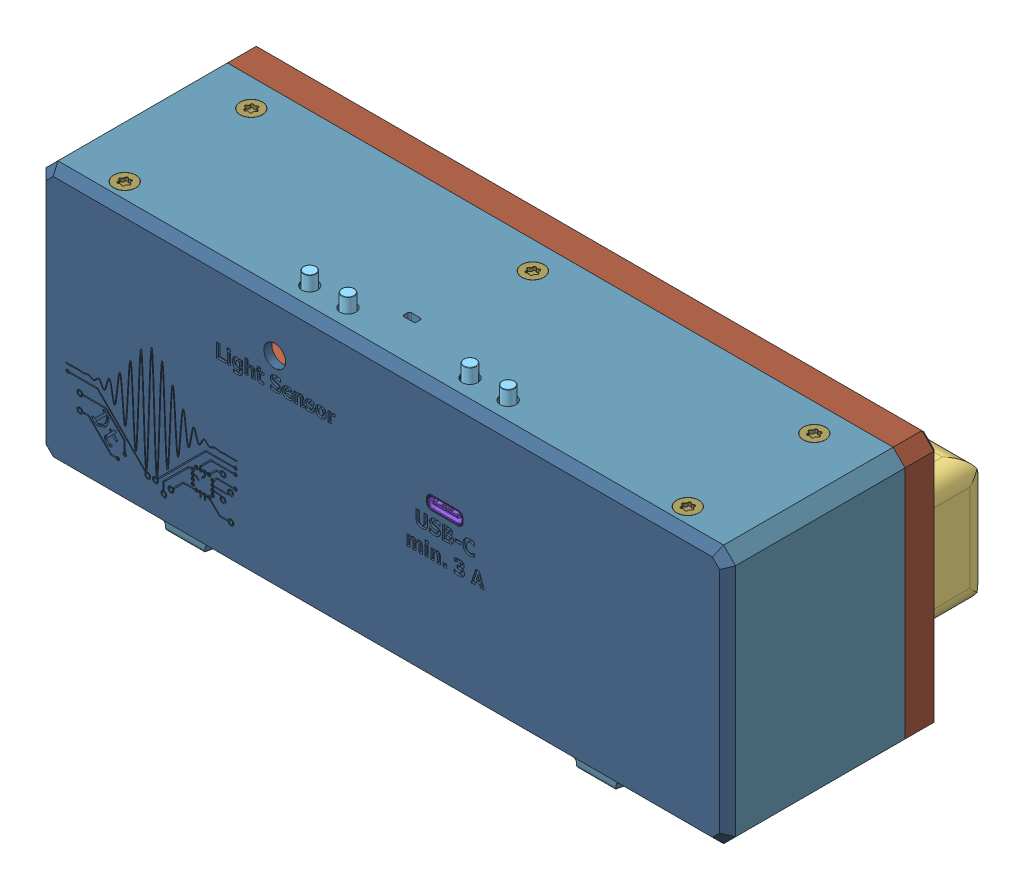
SolidWorks assembly VFDClock_assembly, configuration Default. Lengths in mm.
Overall size (173.3 78.19 72.6).
198 component instances, 48 part files, 101 mates.
Components (placement in the parent):
- Module.step-1: Module.step [Default] at (-86.5239 172.1049 19.515) size (44.41 52.65 19.12)
  - PinSocket_2x03_P2.54mm_Horizontal.step-1: PinSocket_2x03_P2.54mm_Horizontal.step [Default] at (174.37 -130.19 1.595) x (-1 0 0) z (0 0 1) size (12.67 7.62 7.98)
  - D_0603_1608Metric.step-1: D_0603_1608Metric.step [Default] at (176.575 -96 1.595) x (0 -1 0) z (0 0 1) size (1.6 0.87 0.66)
  - TSSOP-16_4.4x5mm_P0.65mm.step-1: TSSOP-16_4.4x5mm_P0.65mm.step [Default] at (164.8375 -99.8 1.595) x (0 -1 0) z (0 0 1) size (6.4 5 1.1)
  - SSOP-18_4.4x6.5mm_P0.65mm.step-1: SSOP-18_4.4x6.5mm_P0.65mm.step [Default] at (164.8375 -91.34 1.595) size (6.4 6.5 1.4)
  - PinSocket_2x03_P2.54mm_Horizontal.step-2: PinSocket_2x03_P2.54mm_Horizontal.step [Default] at (155.23 -116.36 1.595) size (12.67 7.62 7.98)
  - CP_EIA-3216-18_Kemet-A.step-1: CP_EIA-3216-18_Kemet-A.step [Default] at (179.98 -105.55 1.595) x (-1 0 0) z (0 0 1) size (3.2 1.6 1.8)
  - L_1812_4532Metric.step-1: L_1812_4532Metric.step [Default] at (179.98 -101.7575 1.595) x (0 1 0) z (0 0 1) size (4.5 3.2 2.5)
  - PinSocket_2x03_P2.54mm_Horizontal.step-3: PinSocket_2x03_P2.54mm_Horizontal.step [Default] at (155.23 -125.11 1.595) size (12.67 7.62 7.98)
  - D_0603_1608Metric.step-2: D_0603_1608Metric.step [Default] at (157.5 -96 1.595) x (0 -1 0) z (0 0 1) size (1.6 0.87 0.66)
  - PinSocket_2x03_P2.54mm_Horizontal.step-4: PinSocket_2x03_P2.54mm_Horizontal.step [Default] at (174.375 -121.44 1.595) x (-1 0 0) z (0 0 1) size (12.67 7.62 7.98)
  - SOT-223.step-1: SOT-223.step [Default] at (164.8375 -126.74 1.595) x (0 1 0) z (0 0 1) size (7 6.5 1.7)
  - C_0805_2012Metric.step-1: C_0805_2012Metric.step [Default] at (179.98 -98.05 1.595) size (2 1.25 1.25)
  - SOT-223.step-2: SOT-223.step [Default] at (164.8375 -108.8 1.595) x (0 1 0) z (0 0 1) size (7 6.5 1.7)
  - Potentiometer_Bourns_3339P_Vertical.step-1: Potentiometer_Bourns_3339P_Vertical.step [Default] at (162.3275 -117.8 1.595) x (0 -1 0) z (0 0 1) size (7.62 7.62 11.13)
  - CP_EIA-3528-15_AVX-H.step-1: CP_EIA-3528-15_AVX-H.step [Default] at (163.7 -107.7575 -0.085) x (0 -1 0) z (0 0 -1) size (3.5 2.8 1.5)
  - C_0805_2012Metric.step-2: C_0805_2012Metric.step [Default] at (166.5337 -111.3575 -0.085) x (-1 0 0) z (0 0 -1) size (2 1.25 1.25)
  - C_0805_2012Metric.step-3: C_0805_2012Metric.step [Default] at (163.1037 -129.2975 -0.085) x (1 0 0) z (0 0 -1) size (2 1.25 1.25)
  - CP_EIA-3216-18_Kemet-A.step-2: CP_EIA-3216-18_Kemet-A.step [Default] at (166.5375 -125.6975 -0.085) x (0 -1 0) z (0 0 -1) size (3.2 1.6 1.8)
  - C_0805_2012Metric.step-4: C_0805_2012Metric.step [Default] at (163.0662 -111.3575 -0.085) x (1 0 0) z (0 0 -1) size (2 1.25 1.25)
  - CP_EIA-3528-15_AVX-H.step-2: CP_EIA-3528-15_AVX-H.step [Default] at (163.7375 -125.6975 -0.085) x (0 -1 0) z (0 0 -1) size (3.5 2.8 1.5)
  - CP_EIA-3216-18_Kemet-A.step-3: CP_EIA-3216-18_Kemet-A.step [Default] at (166.5 -107.7575 -0.085) x (0 -1 0) z (0 0 -1) size (3.2 1.6 1.8)
  - Module 1.22.step-1: Module 1.22.step [Default] at (182 -101.5275 -0.0739) x (0 1 0) z (-1 0 0) size (21.8 15.2 9.23)
  - C_0805_2012Metric.step-5: C_0805_2012Metric.step [Default] at (166.5712 -129.2975 -0.085) x (-1 0 0) z (0 0 -1) size (2 1.25 1.25)
  - Module_silkscreen.step-1: Module_silkscreen.step [Default] at origin size (44.41 49.93 1.67)
  - Module_PCB.step-1: Module_PCB.step [Default] at origin size (44.4 52.65 1.51)
- Module.step-2: Module.step [Default] at (-210.9239 172.1049 19.515) size (44.41 52.65 19.12)
  - PinSocket_2x03_P2.54mm_Horizontal.step-1: PinSocket_2x03_P2.54mm_Horizontal.step [Default] at (174.37 -130.19 1.595) x (-1 0 0) z (0 0 1) size (12.67 7.62 7.98)
  - D_0603_1608Metric.step-1: D_0603_1608Metric.step [Default] at (176.575 -96 1.595) x (0 -1 0) z (0 0 1) size (1.6 0.87 0.66)
  - TSSOP-16_4.4x5mm_P0.65mm.step-1: TSSOP-16_4.4x5mm_P0.65mm.step [Default] at (164.8375 -99.8 1.595) x (0 -1 0) z (0 0 1) size (6.4 5 1.1)
  - SSOP-18_4.4x6.5mm_P0.65mm.step-1: SSOP-18_4.4x6.5mm_P0.65mm.step [Default] at (164.8375 -91.34 1.595) size (6.4 6.5 1.4)
  - PinSocket_2x03_P2.54mm_Horizontal.step-2: PinSocket_2x03_P2.54mm_Horizontal.step [Default] at (155.23 -116.36 1.595) size (12.67 7.62 7.98)
  - CP_EIA-3216-18_Kemet-A.step-1: CP_EIA-3216-18_Kemet-A.step [Default] at (179.98 -105.55 1.595) x (-1 0 0) z (0 0 1) size (3.2 1.6 1.8)
  - L_1812_4532Metric.step-1: L_1812_4532Metric.step [Default] at (179.98 -101.7575 1.595) x (0 1 0) z (0 0 1) size (4.5 3.2 2.5)
  - PinSocket_2x03_P2.54mm_Horizontal.step-3: PinSocket_2x03_P2.54mm_Horizontal.step [Default] at (155.23 -125.11 1.595) size (12.67 7.62 7.98)
  - D_0603_1608Metric.step-2: D_0603_1608Metric.step [Default] at (157.5 -96 1.595) x (0 -1 0) z (0 0 1) size (1.6 0.87 0.66)
  - PinSocket_2x03_P2.54mm_Horizontal.step-4: PinSocket_2x03_P2.54mm_Horizontal.step [Default] at (174.375 -121.44 1.595) x (-1 0 0) z (0 0 1) size (12.67 7.62 7.98)
  - SOT-223.step-1: SOT-223.step [Default] at (164.8375 -126.74 1.595) x (0 1 0) z (0 0 1) size (7 6.5 1.7)
  - C_0805_2012Metric.step-1: C_0805_2012Metric.step [Default] at (179.98 -98.05 1.595) size (2 1.25 1.25)
  - SOT-223.step-2: SOT-223.step [Default] at (164.8375 -108.8 1.595) x (0 1 0) z (0 0 1) size (7 6.5 1.7)
  - Potentiometer_Bourns_3339P_Vertical.step-1: Potentiometer_Bourns_3339P_Vertical.step [Default] at (162.3275 -117.8 1.595) x (0 -1 0) z (0 0 1) size (7.62 7.62 11.13)
  - CP_EIA-3528-15_AVX-H.step-1: CP_EIA-3528-15_AVX-H.step [Default] at (163.7 -107.7575 -0.085) x (0 -1 0) z (0 0 -1) size (3.5 2.8 1.5)
  - C_0805_2012Metric.step-2: C_0805_2012Metric.step [Default] at (166.5337 -111.3575 -0.085) x (-1 0 0) z (0 0 -1) size (2 1.25 1.25)
  - C_0805_2012Metric.step-3: C_0805_2012Metric.step [Default] at (163.1037 -129.2975 -0.085) x (1 0 0) z (0 0 -1) size (2 1.25 1.25)
  - CP_EIA-3216-18_Kemet-A.step-2: CP_EIA-3216-18_Kemet-A.step [Default] at (166.5375 -125.6975 -0.085) x (0 -1 0) z (0 0 -1) size (3.2 1.6 1.8)
  - C_0805_2012Metric.step-4: C_0805_2012Metric.step [Default] at (163.0662 -111.3575 -0.085) x (1 0 0) z (0 0 -1) size (2 1.25 1.25)
  - CP_EIA-3528-15_AVX-H.step-2: CP_EIA-3528-15_AVX-H.step [Default] at (163.7375 -125.6975 -0.085) x (0 -1 0) z (0 0 -1) size (3.5 2.8 1.5)
  - CP_EIA-3216-18_Kemet-A.step-3: CP_EIA-3216-18_Kemet-A.step [Default] at (166.5 -107.7575 -0.085) x (0 -1 0) z (0 0 -1) size (3.2 1.6 1.8)
  - Module 1.22.step-1: Module 1.22.step [Default] at (182 -101.5275 -0.0739) x (0 1 0) z (-1 0 0) size (21.8 15.2 9.23)
  - C_0805_2012Metric.step-5: C_0805_2012Metric.step [Default] at (166.5712 -129.2975 -0.085) x (-1 0 0) z (0 0 -1) size (2 1.25 1.25)
  - Module_silkscreen.step-1: Module_silkscreen.step [Default] at origin size (44.41 49.93 1.67)
  - Module_PCB.step-1: Module_PCB.step [Default] at origin size (44.4 52.65 1.51)
- Case-1: Case [Default] at (-0.4461 33.1192 -13.485) size (173.3 74.82 42.72)
- VFDClock.step-3: VFDClock.step [Default] at (-132.7539 172.5049 19.515) size (91.66 58.3 22.77)
  - VEML3235SL.step-1: VEML3235SL.step [Default] at (143.765 -88.9975 -0.835) x (1 0 0) z (0 1 0) size (3.18 1.51 1.66)
    - terminal^Vishay_-_VEML3235SL.step.step-1: terminal^Vishay_-_VEML3235SL.step.step [Default] at origin size (3.18 0.48 0.44)
    - base.step.step-1: base.step.step [Default] at origin size (2.95 1.5 1.05)
    - top^Vishay_-_VEML3235SL.step.step-1: top^Vishay_-_VEML3235SL.step.step [Default] at (0 0 1.05) size (2.95 1.5 0.6)
    - logo^Vishay_-_VEML3235SL.step.step-1: logo^Vishay_-_VEML3235SL.step.step [Default] at (0 0 1.65) size (2.81 0.54 0.01)
  - SOT-323_SC-70.step-1: SOT-323_SC-70.step [Default] at (130.3 -90.355 1.595) x (0 -1 0) z (0 0 1) size (2 2 1.05)
  - LED_0603_1608Metric.step-1: LED_0603_1608Metric.step [Default] at (164.03 -88.68 1.595) x (-1 0 0) z (0 0 1) size (1.6 0.8 1.1)
  - PinHeader_2x03_P2.54mm_Horizontal.step-1: PinHeader_2x03_P2.54mm_Horizontal.step [Default] at (182.08 -125.51 1.595) size (12.9 7.62 8.08)
  - D_0603_1608Metric.step-1: D_0603_1608Metric.step [Default] at (144.73 -127.58 1.595) size (1.6 0.87 0.66)
  - TSSOP-16_4.4x5mm_P0.65mm.step-1: TSSOP-16_4.4x5mm_P0.65mm.step [Default] at (140.03 -116.68 1.595) x (0 1 0) z (0 0 1) size (6.4 5 1.1)
  - SSOP-18_4.4x6.5mm_P0.65mm.step-1: SSOP-18_4.4x6.5mm_P0.65mm.step [Default] at (148.79 -116.68 1.595) x (0 -1 0) z (0 0 1) size (6.4 6.5 1.4)
  - R_0805_2012Metric.step-1: R_0805_2012Metric.step [Default] at (160.53 -90.48 1.595) x (-1 0 0) z (0 0 1) size (2 1.2 0.45)
  - PinHeader_2x03_P2.54mm_Horizontal.step-2: PinHeader_2x03_P2.54mm_Horizontal.step [Default] at (115.58 -121.84 1.595) x (-1 0 0) z (0 0 1) size (12.9 7.62 8.08)
  - SSOP-18_4.4x6.5mm_P0.65mm.step-2: SSOP-18_4.4x6.5mm_P0.65mm.step [Default] at (158.43 -116.68 1.595) x (0 -1 0) z (0 0 1) size (6.4 6.5 1.4)
  - SW_Tactile_SPST_Angled_PTS645Vx83-2LFS.step-1: SW_Tactile_SPST_Angled_PTS645Vx83-2LFS.step [Default] at (131.33 -82.0425 1.595) size (7.4 12.4 11)
  - R_0805_2012Metric.step-2: R_0805_2012Metric.step [Default] at (162.53 -96.8 1.595) size (2 1.2 0.45)
  - PTS810SJK250SMTR_LFS-v2.step-1: PTS810SJK250SMTR_LFS-v2.step [Default] at (134.63 -88.48 1.595) x (1 0 0) z (0 -1 0) size (4.6 2.7 3.2)
  - R_0805_2012Metric.step-3: R_0805_2012Metric.step [Default] at (137.43 -97.18 1.595) x (0 -1 0) z (0 0 1) size (2 1.2 0.45)
  - R_0805_2012Metric.step-4: R_0805_2012Metric.step [Default] at (137.43 -100.58 1.595) x (0 1 0) z (0 0 1) size (2 1.2 0.45)
  - SW_Tactile_SPST_Angled_PTS645Vx83-2LFS.step-2: SW_Tactile_SPST_Angled_PTS645Vx83-2LFS.step [Default] at (161.98 -82.0425 1.595) size (7.4 12.4 11)
  - PinSocket_2x04_P2.54mm_Vertical_SMD.step-1: PinSocket_2x04_P2.54mm_Vertical_SMD.step [Default] at (171.5 -91.1 1.595) x (0 1 0) z (0 0 1) size (6.8 10.16 7.45)
  - LED_0603_1608Metric.step-2: LED_0603_1608Metric.step [Default] at (160.53 -88.68 1.595) x (-1 0 0) z (0 0 1) size (1.6 0.8 1.1)
  - SW_Tactile_SPST_Angled_PTS645Vx83-2LFS.step-3: SW_Tactile_SPST_Angled_PTS645Vx83-2LFS.step [Default] at (171.59 -82.0425 1.595) size (7.4 12.4 11)
  - CP_EIA-3216-18_Kemet-A.step-1: CP_EIA-3216-18_Kemet-A.step [Default] at (179.6925 -112.1 1.595) x (0 -1 0) z (0 0 1) size (3.2 1.6 1.8)
  - UJ20-C-V-C-2-SMT-TR-v2.step-1: UJ20-C-V-C-2-SMT-TR-v2.step [Default] at (164.43 -102.6 1.595) x (1 0 0) z (0 -1 0) size (9.5 12.25 4.16)
  - ESP32-S3-WROOM-1.step-1: ESP32-S3-WROOM-1.step [Default] at (148.93 -93.58 1.595) size (18 25.5 3.1)
  - C_0805_2012Metric.step-1: C_0805_2012Metric.step [Default] at (131.13 -95.18 1.595) x (-1 0 0) z (0 0 1) size (2 1.25 1.25)
  - R_0805_2012Metric.step-5: R_0805_2012Metric.step [Default] at (166.23 -96.8 1.595) size (2 1.2 0.45)
  - R_0805_2012Metric.step-6: R_0805_2012Metric.step [Default] at (164.03 -90.48 1.595) x (-1 0 0) z (0 0 1) size (2 1.2 0.45)
  - R_0805_2012Metric.step-7: R_0805_2012Metric.step [Default] at (121.63 -94.28 1.595) x (-1 0 0) z (0 0 1) size (2 1.2 0.45)
  - C_0805_2012Metric.step-2: C_0805_2012Metric.step [Default] at (129.33 -102.58 1.595) x (-1 0 0) z (0 0 1) size (2 1.25 1.25)
  - R_0805_2012Metric.step-8: R_0805_2012Metric.step [Default] at (162.53 -98.8 1.595) size (2 1.2 0.45)
  - R_0805_2012Metric.step-9: R_0805_2012Metric.step [Default] at (166.23 -98.8 1.595) x (-1 0 0) z (0 0 1) size (2 1.2 0.45)
  - L_1812_4532Metric.step-1: L_1812_4532Metric.step [Default] at (175.9 -112.1 1.595) x (-1 0 0) z (0 0 1) size (4.5 3.2 2.5)
  - PinHeader_2x03_P2.54mm_Horizontal.step-3: PinHeader_2x03_P2.54mm_Horizontal.step [Default] at (115.58 -130.59 1.595) x (-1 0 0) z (0 0 1) size (12.9 7.62 8.08)
  - SOIC-8_3.9x4.9mm_P1.27mm.step-1: SOIC-8_3.9x4.9mm_P1.27mm.step [Default] at (131.13 -98.88 1.595) size (6 4.9 1.75)
  - C_0805_2012Metric.step-3: C_0805_2012Metric.step [Default] at (132.93 -102.58 1.595) size (2 1.25 1.25)
  - PTS810SJK250SMTR_LFS-v2.step-2: PTS810SJK250SMTR_LFS-v2.step [Default] at (134.63 -92.28 1.595) x (1 0 0) z (0 -1 0) size (4.6 2.7 3.2)
  - D_0603_1608Metric.step-2: D_0603_1608Metric.step [Default] at (147.83 -127.58 1.595) size (1.6 0.87 0.66)
  - PinHeader_2x03_P2.54mm_Horizontal.step-4: PinHeader_2x03_P2.54mm_Horizontal.step [Default] at (182.08 -116.76 1.595) size (12.9 7.62 8.08)
  - SOT-223.step-1: SOT-223.step [Default] at (183.7675 -100.4 1.595) x (0 -1 0) z (0 0 1) size (7 6.5 1.7)
  - PinSocket_2x02_P2.54mm_Vertical_SMD.step-1: PinSocket_2x02_P2.54mm_Vertical_SMD.step [Default] at (183.83 -83.28 1.595) size (6.8 5.08 7.45)
  - C_0805_2012Metric.step-4: C_0805_2012Metric.step [Default] at (172.1925 -112.1 1.595) x (0 1 0) z (0 0 1) size (2 1.25 1.25)
  - SOT-223.step-2: SOT-223.step [Default] at (174.3 -100.4 1.595) x (0 -1 0) z (0 0 1) size (7 6.5 1.7)
  - R_LDR_5.1x4.3mm_P3.4mm_Vertical.step-1: R_LDR_5.1x4.3mm_P3.4mm_Vertical.step [Default] at (121.63 -88.705 1.595) x (0 -1 0) z (0 0 1) size (5.1 4.3 7)
  - SW_Tactile_SPST_Angled_PTS645Vx83-2LFS.step-4: SW_Tactile_SPST_Angled_PTS645Vx83-2LFS.step [Default] at (121.72 -82.0425 1.595) size (7.4 12.4 11)
  - Potentiometer_Bourns_3339P_Vertical.step-1: Potentiometer_Bourns_3339P_Vertical.step [Default] at (183.805 -88.575 1.595) x (-1 0 0) z (0 0 1) size (7.62 7.62 11.13)
  - R_0805_2012Metric.step-10: R_0805_2012Metric.step [Default] at (142.775 -91.1975 -0.085) x (0 1 0) z (0 0 -1) size (2 1.2 0.45)
  - C_0805_2012Metric.step-5: C_0805_2012Metric.step [Default] at (129.13 -90.48 -0.085) x (0 -1 0) z (0 0 -1) size (2 1.25 1.25)
  - R_0805_2012Metric.step-11: R_0805_2012Metric.step [Default] at (164.22 -84.78 -0.085) x (0 1 0) z (0 0 -1) size (2 1.2 0.45)
  - Fuse_0603_1608Metric.step-1: Fuse_0603_1608Metric.step [Default] at (162.43 -106.28 -0.085) x (1 0 0) z (0 0 -1) size (1.6 0.8 0.45)
  - R_0805_2012Metric.step-12: R_0805_2012Metric.step [Default] at (173.83 -84.78 -0.085) x (0 1 0) z (0 0 -1) size (2 1.2 0.45)
  - SOT-323_SC-70.step-2: SOT-323_SC-70.step [Default] at (164.22 -81.18 -0.085) x (0 -1 0) z (0 0 -1) size (2 2 1.05)
  - CP_EIA-3528-15_AVX-H.step-1: CP_EIA-3528-15_AVX-H.step [Default] at (175.2 -100.15 -0.085) x (0 1 0) z (0 0 -1) size (3.5 2.8 1.5)
  - SOT-323_SC-70.step-3: SOT-323_SC-70.step [Default] at (133.59 -81.18 -0.085) x (0 -1 0) z (0 0 -1) size (2 2 1.05)
  - R_0805_2012Metric.step-13: R_0805_2012Metric.step [Default] at (133.605 -84.78 -0.085) x (0 1 0) z (0 0 -1) size (2 1.2 0.45)
  - C_0805_2012Metric.step-6: C_0805_2012Metric.step [Default] at (172.5 -103.75 -0.085) x (1 0 0) z (0 0 -1) size (2 1.25 1.25)
  - R_0805_2012Metric.step-14: R_0805_2012Metric.step [Default] at (126.43 -88.48 -0.085) x (-1 0 0) z (0 0 -1) size (2 1.2 0.45)
  - SOT-323_SC-70.step-4: SOT-323_SC-70.step [Default] at (173.83 -81.18 -0.085) x (0 -1 0) z (0 0 -1) size (2 2 1.05)
  - JST_XH_B4B-XH-A_1x04_P2.50mm_Vertical.step-1: JST_XH_B4B-XH-A_1x04_P2.50mm_Vertical.step [Default] at (168.78 -121.58 -0.085) x (0 -1 0) z (0 0 -1) size (12.4 5.75 10.4)
  - SC-74-6_1.55x2.9mm_P0.95mm.step-1: SC-74-6_1.55x2.9mm_P0.95mm.step [Default] at (162.43 -110.2 -0.085) x (0 1 0) z (0 0 -1) size (2.7 2.9 1.18)
  - C_0805_2012Metric.step-7: C_0805_2012Metric.step [Default] at (137.63 -92.28 -0.085) x (0 -1 0) z (0 0 -1) size (2 1.25 1.25)
  - R_0805_2012Metric.step-15: R_0805_2012Metric.step [Default] at (133.5483 -88.63 -0.085) x (0 1 0) z (0 0 -1) size (2 1.2 0.45)
  - CP_EIA-3216-18_Kemet-A.step-2: CP_EIA-3216-18_Kemet-A.step [Default] at (146.96 -89.3475 -0.085) x (0 -1 0) z (0 0 -1) size (3.2 1.6 1.8)
  - C_0805_2012Metric.step-8: C_0805_2012Metric.step [Default] at (185.6 -103.7625 -0.085) x (-1 0 0) z (0 0 -1) size (2 1.25 1.25)
  - BatteryHolder_Keystone_3034_1x20mm.step-1: BatteryHolder_Keystone_3034_1x20mm.step [Default] at (128.93 -106.7 -0.085) x (0 1 0) z (0 0 -1) size (23.24 16.41 4)
  - CP_EIA-3216-18_Kemet-A.step-3: CP_EIA-3216-18_Kemet-A.step [Default] at (182 -100.1625 -0.085) x (0 -1 0) z (0 0 -1) size (3.2 1.6 1.8)
  - C_0805_2012Metric.step-9: C_0805_2012Metric.step [Default] at (176.2 -103.75 -0.085) x (-1 0 0) z (0 0 -1) size (2 1.25 1.25)
  - R_0805_2012Metric.step-16: R_0805_2012Metric.step [Default] at (123.995 -84.78 -0.085) x (0 1 0) z (0 0 -1) size (2 1.2 0.45)
  - C_0805_2012Metric.step-10: C_0805_2012Metric.step [Default] at (149.06 -89.3475 -0.085) x (0 -1 0) z (0 0 -1) size (2 1.25 1.25)
  - SOT-323_SC-70.step-5: SOT-323_SC-70.step [Default] at (123.98 -81.18 -0.085) x (0 -1 0) z (0 0 -1) size (2 2 1.05)
  - C_0805_2012Metric.step-11: C_0805_2012Metric.step [Default] at (137.7 -88.6255 -0.085) x (0 1 0) z (0 0 -1) size (2 1.25 1.25)
  - CP_EIA-3528-15_AVX-H.step-2: CP_EIA-3528-15_AVX-H.step [Default] at (184.9 -100.1625 -0.085) x (0 1 0) z (0 0 -1) size (3.5 2.8 1.5)
  - C_0805_2012Metric.step-12: C_0805_2012Metric.step [Default] at (135.63 -92.28 -0.085) x (0 -1 0) z (0 0 -1) size (2 1.25 1.25)
  - CP_EIA-3216-18_Kemet-A.step-4: CP_EIA-3216-18_Kemet-A.step [Default] at (135.6183 -88 -0.085) x (0 1 0) z (0 0 -1) size (3.2 1.6 1.8)
  - SHT45-AD1B-R2.step-1: SHT45-AD1B-R2.step [Default] at (126.43 -90.48 -0.085) x (1 0 0) z (0 1 0) size (1.5 0.69 1.5)
  - CP_EIA-3216-18_Kemet-A.step-5: CP_EIA-3216-18_Kemet-A.step [Default] at (172.3 -100.15 -0.085) x (0 -1 0) z (0 0 -1) size (3.2 1.6 1.8)
  - R_0805_2012Metric.step-17: R_0805_2012Metric.step [Default] at (144.83 -91.1975 -0.085) x (0 1 0) z (0 0 -1) size (2 1.2 0.45)
  - R_0805_2012Metric.step-18: R_0805_2012Metric.step [Default] at (133.63 -92.28 -0.085) x (0 1 0) z (0 0 -1) size (2 1.2 0.45)
  - JST_XH_B4B-XH-A_1x04_P2.50mm_Vertical.step-2: JST_XH_B4B-XH-A_1x04_P2.50mm_Vertical.step [Default] at (128.84 -121.58 -0.085) x (0 -1 0) z (0 0 -1) size (12.4 5.75 10.4)
  - VFDClock 1.77.step-1: VFDClock 1.77.step [Default] at (175.67 -110.08 -0.0739) x (-1 0 0) z (0 -1 0) size (21.8 15.2 9.23)
  - C_0805_2012Metric.step-13: C_0805_2012Metric.step [Default] at (181.9 -103.7625 -0.085) x (1 0 0) z (0 0 -1) size (2 1.25 1.25)
  - R_0805_2012Metric.step-19: R_0805_2012Metric.step [Default] at (126.43 -92.48 -0.085) x (-1 0 0) z (0 0 -1) size (2 1.2 0.45)
  - VFDClock_silkscreen.step-1: VFDClock_silkscreen.step [Default] at origin size (80.01 52.34 1.76)
  - VFDClock_PCB.step-1: VFDClock_PCB.step [Default] at origin size (80 52.65 1.51)
- IV-22-1: IV-22 [Default] at (-53.4239 62.8549 -13.485) x (-1 0 0) z (0 0 -1) size (22 32 36)
- PL31A-P-1: PL31A-P [Default] at (-73.9735 62.8549 -6.685) x (-1 0 0) z (0 0 -1) size (22 40.86 14.1)
- PL31A-P-19: PL31A-P [Default] at (-50.5735 62.8549 -6.685) x (-1 0 0) z (0 0 -1) size (22 40.86 14.1)
- PL31A-P-20: PL31A-P [Default] at (-16.1735 62.8549 -6.685) x (-1 0 0) z (0 0 -1) size (22 40.86 14.1)
- PL31A-P-21: PL31A-P [Default] at (7.2265 62.8549 -6.685) x (-1 0 0) z (0 0 -1) size (22 40.86 14.1)
- PL31A-P-22: PL31A-P [Default] at (41.6265 62.8549 -6.685) x (-1 0 0) z (0 0 -1) size (22 40.86 14.1)
- IV-22-23: IV-22 [Default] at (85.5761 62.8549 -13.485) x (-1 0 0) z (0 0 -1) size (22 32 36)
- PL31A-P-23: PL31A-P [Default] at (65.0265 62.8549 -6.685) x (-1 0 0) z (0 0 -1) size (22 40.86 14.1)
- Separator.step-1: Separator.step [Default] at (-67.0239 202.8549 -11.685) x (0 -1 0) z (0 0 -1) size (32 10 9.38)
  - LED_Inolux_IN-PI554FCH_PLCC4_5.0x5.0mm_P3.2mm.step-1: LED_Inolux_IN-PI554FCH_PLCC4_5.0x5.0mm_P3.2mm.step [Default] at (144.6 -112 1.595) x (0 -1 0) z (0 0 1) size (5.4 5 1.7)
  - LED_Inolux_IN-PI554FCH_PLCC4_5.0x5.0mm_P3.2mm.step-2: LED_Inolux_IN-PI554FCH_PLCC4_5.0x5.0mm_P3.2mm.step [Default] at (135 -112 1.595) x (0 1 0) z (0 0 1) size (5.4 5 1.7)
  - PinHeader_2x02_P2.00mm_Vertical.step-1: PinHeader_2x02_P2.00mm_Vertical.step [Default] at (138.8 -111.1 -0.085) x (0 -1 0) z (0 0 -1) size (4 4 8.8)
  - R_0805_2012Metric.step-1: R_0805_2012Metric.step [Default] at (140 -108.6 -0.085) x (-1 0 0) z (0 0 -1) size (2 1.2 0.45)
  - SOT-23.step-1: SOT-23.step [Default] at (135.3 -112 -0.085) x (-1 0 0) z (0 0 -1) size (2.5 3 1.2)
  - C_0805_2012Metric.step-1: C_0805_2012Metric.step [Default] at (143.3 -112 -0.085) x (0 -1 0) z (0 0 -1) size (2 1.25 1.25)
  - R_0805_2012Metric.step-2: R_0805_2012Metric.step [Default] at (140 -115.6 -0.085) x (-1 0 0) z (0 0 -1) size (2 1.2 0.45)
  - C_0805_2012Metric.step-2: C_0805_2012Metric.step [Default] at (132.3 -112 -0.085) x (0 -1 0) z (0 0 -1) size (2 1.25 1.25)
  - Separator_silkscreen.step-1: Separator_silkscreen.step [Default] at origin size (25.16 9.28 1.67)
  - Separator_PCB.step-1: Separator_PCB.step [Default] at origin size (32 10 1.51)
- Separator.step-2: Separator.step [Default] at (-124.8239 202.8549 -11.685) x (0 -1 0) z (0 0 -1) size (32 10 9.38)
  - LED_Inolux_IN-PI554FCH_PLCC4_5.0x5.0mm_P3.2mm.step-1: LED_Inolux_IN-PI554FCH_PLCC4_5.0x5.0mm_P3.2mm.step [Default] at (144.6 -112 1.595) x (0 -1 0) z (0 0 1) size (5.4 5 1.7)
  - LED_Inolux_IN-PI554FCH_PLCC4_5.0x5.0mm_P3.2mm.step-2: LED_Inolux_IN-PI554FCH_PLCC4_5.0x5.0mm_P3.2mm.step [Default] at (135 -112 1.595) x (0 1 0) z (0 0 1) size (5.4 5 1.7)
  - PinHeader_2x02_P2.00mm_Vertical.step-1: PinHeader_2x02_P2.00mm_Vertical.step [Default] at (138.8 -111.1 -0.085) x (0 -1 0) z (0 0 -1) size (4 4 8.8)
  - R_0805_2012Metric.step-1: R_0805_2012Metric.step [Default] at (140 -108.6 -0.085) x (-1 0 0) z (0 0 -1) size (2 1.2 0.45)
  - SOT-23.step-1: SOT-23.step [Default] at (135.3 -112 -0.085) x (-1 0 0) z (0 0 -1) size (2.5 3 1.2)
  - C_0805_2012Metric.step-1: C_0805_2012Metric.step [Default] at (143.3 -112 -0.085) x (0 -1 0) z (0 0 -1) size (2 1.25 1.25)
  - R_0805_2012Metric.step-2: R_0805_2012Metric.step [Default] at (140 -115.6 -0.085) x (-1 0 0) z (0 0 -1) size (2 1.2 0.45)
  - C_0805_2012Metric.step-2: C_0805_2012Metric.step [Default] at (132.3 -112 -0.085) x (0 -1 0) z (0 0 -1) size (2 1.25 1.25)
  - Separator_silkscreen.step-1: Separator_silkscreen.step [Default] at origin size (25.16 9.28 1.67)
  - Separator_PCB.step-1: Separator_PCB.step [Default] at origin size (32 10 1.51)
- CaseCover-1: CaseCover [Default] at (19.2559 33.9844 29.115) size (173.3 65 9.8)
- FacePlate-1: FacePlate [Default] at (-21.2345 44.7045 -13.485) x (-1 0 0) z (0 0 -1) size (173.3 65 18.8)
- IV-22-24: IV-22 [Default] at (27.7761 62.8549 -13.485) x (-1 0 0) z (0 0 -1) size (22 32 36)
- IV-22-25: IV-22 [Default] at (-30.0239 62.8549 -13.485) x (-1 0 0) z (0 0 -1) size (22 32 36)
- IV-22-26: IV-22 [Default] at (4.3761 62.8549 -13.485) x (-1 0 0) z (0 0 -1) size (22 32 36)
- IV-22-27: IV-22 [Default] at (62.1761 62.8549 -13.485) x (-1 0 0) z (0 0 -1) size (22 32 36)
- M3x10_Torx-1: M3x10_Torx [Default] at (16.0761 89.4921 -6.585) x (0 -1 0) z (0 0 1) size (10 5.5 5.5)
- M3x10_Torx-2: M3x10_Torx [Default] at (16.0761 36.2176 25.215) x (0 1 0) z (0 0 1) size (10 5.5 5.5)
- M3x10_Torx-4: M3x10_Torx [Default] at (-54.6739 36.2176 -6.585) x (0 1 0) z (0 0 1) size (10 5.5 5.5)
- M3x10_Torx-5: M3x10_Torx [Default] at (86.8261 89.4921 25.215) x (0 -1 0) z (0 0 1) size (10 5.5 5.5)
- M3x10_Torx-6: M3x10_Torx [Default] at (-54.6739 89.4921 -6.585) x (0 -1 0) z (0.1614 0 0.986889) size (10 5.5 5.5)
- M3x10_Torx-7: M3x10_Torx [Default] at (86.8261 36.2176 25.215) x (0 1 0) z (0 0 1) size (10 5.5 5.5)
- M3x10_Torx-8: M3x10_Torx [Default] at (-54.6739 36.2176 25.215) x (0 1 0) z (0 0 1) size (10 5.5 5.5)
- M3x10_Torx-9: M3x10_Torx [Default] at (16.0761 36.2176 -6.585) x (0 1 0) z (0 0 1) size (10 5.5 5.5)
- M3x10_Torx-10: M3x10_Torx [Default] at (86.8261 36.2176 -6.585) x (0 1 0) z (0 0 1) size (10 5.5 5.5)
- M3x10_Torx-11: M3x10_Torx [Default] at (-54.6739 89.4921 25.215) x (0 -1 0) z (0 0 1) size (10 5.5 5.5)
- M3x10_Torx-12: M3x10_Torx [Default] at (86.8261 89.4921 -6.585) x (0 -1 0) z (0 0 1) size (10 5.5 5.5)
- M3x10_Torx-13: M3x10_Torx [Default] at (91.9261 46.3549 -7.6223) x (0 0 1) z (0 1 0) size (10 5.5 5.5)
- M3x10_Torx-14: M3x10_Torx [Default] at (79.2261 79.3549 -7.6223) x (0 0 1) z (0 1 0) size (10 5.5 5.5)
- M3x10_Torx-15: M3x10_Torx [Default] at (55.8261 79.3549 -7.6223) x (0 0 1) z (0 1 0) size (10 5.5 5.5)
- M3x10_Torx-16: M3x10_Torx [Default] at (21.4261 79.3549 -7.6223) x (0 0 1) z (0 1 0) size (10 5.5 5.5)
- M3x10_Torx-17: M3x10_Torx [Default] at (-1.9739 79.3549 -7.6223) x (0 0 1) z (0 1 0) size (10 5.5 5.5)
- M3x10_Torx-18: M3x10_Torx [Default] at (-36.3739 79.3549 -7.6223) x (0 0 1) z (0 1 0) size (10 5.5 5.5)
- M3x10_Torx-19: M3x10_Torx [Default] at (68.5261 46.3549 -7.6223) x (0 0 1) z (0 1 0) size (10 5.5 5.5)
- M3x10_Torx-20: M3x10_Torx [Default] at (34.1261 46.3549 -7.6223) x (0 0 1) z (0 1 0) size (10 5.5 5.5)
- M3x10_Torx-21: M3x10_Torx [Default] at (10.7261 46.3549 -7.6223) x (0 0 1) z (0 1 0) size (10 5.5 5.5)
- M3x10_Torx-22: M3x10_Torx [Default] at (-23.6739 46.3549 -7.6223) x (0 0 1) z (0 1 0) size (10 5.5 5.5)
- M3x10_Torx-23: M3x10_Torx [Default] at (-47.0739 46.3549 -7.6223) x (0 0 1) z (0 1 0) size (10 5.5 5.5)
- M3x10_Torx-24: M3x10_Torx [Default] at (-59.7739 79.3549 -7.6223) x (0 0 1) z (0 1 0) size (10 5.5 5.5)
Mates (geometry in assembly coordinates):
- Concentric11: concentric anti-aligned: cylinder of Module.step-2/Module_PCB.step-1 through (-64.5739 89.3549 19.469) axis (0 0 -1) radius 1.6; cylinder of Case-1 through (-64.5739 89.3549 10.515) axis (0 0 1) radius 2
- Coincident17: coincident anti-aligned: plane of Module.step-2/Module_PCB.step-1 through (-210.9239 172.1049 19.515) normal (0 0 -1); plane of Case-1 through (-64.5739 89.3549 19.515) normal (0 0 1)
- Parallel8: parallel anti-aligned: plane of Module.step-2/Module_PCB.step-1 through (-23.9239 40.4249 19.515) normal (0 -1 0); plane of Case-1 through (-70.5739 32.3549 46.515) normal (0 1 0)
- Coincident18: coincident anti-aligned: plane of Module.step-2/Module_PCB.step-1 through (-23.9239 93.0749 19.515) normal (1 0 0); plane of VFDClock.step-3/VFDClock_PCB.step-1 through (-23.9239 40.4249 19.515) normal (-1 0 0)
- Coincident25: coincident aligned: plane of Module.step-2/Module_PCB.step-1 through (-210.9239 172.1049 21.025) normal (0 0 1); plane of VFDClock.step-3/VFDClock_PCB.step-1 through (-132.7539 172.5049 21.025) normal (0 0 1)
- Coincident26: coincident aligned: plane of Module.step-2/Module_PCB.step-1 through (-68.3239 93.0749 19.515) normal (0 1 0); plane of VFDClock.step-3/VFDClock_PCB.step-1 through (-23.9239 93.0749 19.515) normal (0 1 0)
- Coincident21: coincident anti-aligned: plane of Module.step-1/Module_PCB.step-1 through (56.0761 40.4249 19.515) normal (-1 0 0); plane of VFDClock.step-3/VFDClock_PCB.step-1 through (56.0761 93.0749 19.515) normal (1 0 0)
- Coincident27: coincident aligned: plane of Module.step-1/Module_PCB.step-1 through (-86.5239 172.1049 21.025) normal (0 0 1); plane of VFDClock.step-3/VFDClock_PCB.step-1 through (-132.7539 172.5049 21.025) normal (0 0 1)
- Coincident28: coincident aligned: plane of Module.step-1/Module_PCB.step-1 through (56.0761 93.0749 19.515) normal (0 1 0); plane of VFDClock.step-3/VFDClock_PCB.step-1 through (-23.9239 93.0749 19.515) normal (0 1 0)
- Concentric12: concentric aligned: circle of IV-22-1; cylinder of PL31A-P-1 through (-53.4239 62.8549 4.1932) axis (0 0 -1) radius 2.75
- Parallel13: parallel aligned: plane of IV-22-1 through (-64.4239 73.8549 -41.485) normal (-1 0 0); plane of PL31A-P-1 through (-64.4239 62.8549 -10.485) normal (-1 0 0)
- Coincident23: coincident anti-aligned: plane of IV-22-1 through (-59.4239 51.8549 -13.485) normal (0 0 1); plane of PL31A-P-1 through (-53.4239 62.8549 -13.485) normal (0 0 -1)
- Concentric37: concentric aligned: circle of IV-22-23; cylinder of PL31A-P-23 through (85.5761 62.8549 4.1932) axis (0 0 -1) radius 2.75
- Parallel42: parallel aligned: plane of IV-22-23 through (74.5761 73.8549 -41.485) normal (-1 0 0); plane of PL31A-P-23 through (74.5761 62.8549 -10.485) normal (-1 0 0)
- Coincident64: coincident anti-aligned: plane of IV-22-23 through (79.5761 51.8549 -13.485) normal (0 0 1); plane of PL31A-P-23 through (85.5761 62.8549 -13.485) normal (0 0 -1)
- Concentric40: concentric aligned: cylinder of Case-1 through (-59.7739 79.3549 25.6857) axis (0 0 -1) radius 1.6; cylinder of PL31A-P-1 through (-59.7739 79.3549 -2.0181) axis (0 0 -1) radius 1.65
- Coincident84: coincident aligned: plane of Case-1 through (-0.4461 33.1192 -13.485) normal (0 0 -1); plane of PL31A-P-1 through (-53.4239 62.8549 -13.485) normal (0 0 -1)
- Concentric41: concentric aligned: cylinder of Case-1 through (-47.0739 46.3549 25.6857) axis (0 0 -1) radius 1.6; cylinder of PL31A-P-1 through (-47.0739 46.3549 -2.0181) axis (0 0 -1) radius 1.65
- Coincident85: coincident aligned: plane of Case-1 through (-0.4461 33.1192 -13.485) normal (0 0 -1); plane of PL31A-P-19 through (-30.0239 62.8549 -13.485) normal (0 0 -1)
- Concentric42: concentric aligned: cylinder of Case-1 through (-36.3739 79.3549 25.6857) axis (0 0 -1) radius 1.6; cylinder of PL31A-P-19 through (-36.3739 79.3549 -2.0181) axis (0 0 -1) radius 1.65
- Concentric43: concentric aligned: cylinder of Case-1 through (-23.6739 46.3549 25.6857) axis (0 0 -1) radius 1.6; cylinder of PL31A-P-19 through (-23.6739 46.3549 -2.0181) axis (0 0 -1) radius 1.65
- Coincident86: coincident aligned: plane of Case-1 through (-0.4461 33.1192 -13.485) normal (0 0 -1); plane of PL31A-P-20 through (4.3761 62.8549 -13.485) normal (0 0 -1)
- Concentric44: concentric aligned: cylinder of Case-1 through (-1.9739 79.3549 25.6857) axis (0 0 -1) radius 1.6; cylinder of PL31A-P-20 through (-1.9739 79.3549 -2.0181) axis (0 0 -1) radius 1.65
- Concentric45: concentric aligned: cylinder of Case-1 through (10.7261 46.3549 25.6857) axis (0 0 -1) radius 1.6; cylinder of PL31A-P-20 through (10.7261 46.3549 -2.0181) axis (0 0 -1) radius 1.65
- Coincident87: coincident aligned: plane of Case-1 through (-0.4461 33.1192 -13.485) normal (0 0 -1); plane of PL31A-P-21 through (27.7761 62.8549 -13.485) normal (0 0 -1)
- Concentric46: concentric aligned: cylinder of Case-1 through (21.4261 79.3549 25.6857) axis (0 0 -1) radius 1.6; cylinder of PL31A-P-21 through (21.4261 79.3549 -2.0181) axis (0 0 -1) radius 1.65
- Concentric47: concentric aligned: cylinder of Case-1 through (34.1261 46.3549 25.6857) axis (0 0 -1) radius 1.6; cylinder of PL31A-P-21 through (34.1261 46.3549 -2.0181) axis (0 0 -1) radius 1.65
- Concentric48: concentric aligned: cylinder of Case-1 through (55.8261 79.3549 25.6857) axis (0 0 -1) radius 1.6; cylinder of PL31A-P-22 through (55.8261 79.3549 -2.0181) axis (0 0 -1) radius 1.65
- Coincident88: coincident aligned: plane of Case-1 through (-0.4461 33.1192 -13.485) normal (0 0 -1); plane of PL31A-P-22 through (62.1761 62.8549 -13.485) normal (0 0 -1)
- Concentric49: concentric aligned: cylinder of Case-1 through (68.5261 46.3549 25.6857) axis (0 0 -1) radius 1.6; cylinder of PL31A-P-22 through (68.5261 46.3549 -2.0181) axis (0 0 -1) radius 1.65
- Coincident89: coincident aligned: plane of Case-1 through (-0.4461 33.1192 -13.485) normal (0 0 -1); plane of PL31A-P-23 through (85.5761 62.8549 -13.485) normal (0 0 -1)
- Concentric50: concentric aligned: cylinder of Case-1 through (79.2261 79.3549 25.6857) axis (0 0 -1) radius 1.6; cylinder of PL31A-P-23 through (79.2261 79.3549 -2.0181) axis (0 0 -1) radius 1.65
- Concentric51: concentric aligned: cylinder of Case-1 through (91.9261 46.3549 25.6857) axis (0 0 -1) radius 1.6; cylinder of PL31A-P-23 through (91.9261 46.3549 -2.0181) axis (0 0 -1) radius 1.65
- Coincident90: coincident anti-aligned: plane of Case-1 through (-0.4461 33.1192 -11.685) normal (0 0 -1); plane of Separator.step-1/Separator_PCB.step-1 through (-67.0239 202.8549 -11.685) normal (0 0 1)
- Coincident91: coincident anti-aligned: plane of Case-1 through (-0.4461 33.1192 -11.685) normal (0 0 -1); plane of Separator.step-2/Separator_PCB.step-1 through (-124.8239 202.8549 -11.685) normal (0 0 1)
- Concentric54: concentric anti-aligned: cylinder of Case-1 through (44.9761 74.8549 9.6396) axis (0 0 -1) radius 1.6; cylinder of Separator.step-1/Separator_PCB.step-1 through (44.9761 74.8549 -11.639) axis (0 0 1) radius 1.6
- Concentric55: concentric anti-aligned: cylinder of Case-1 through (-12.8239 74.8549 9.6396) axis (0 0 -1) radius 1.6; cylinder of Separator.step-2/Separator_PCB.step-1 through (-12.8239 74.8549 -11.639) axis (0 0 1) radius 1.6
- Coincident92: coincident anti-aligned: plane of Case-1 through (-0.4461 33.1192 29.115) normal (0 0 1); plane of CaseCover-1 through (19.2559 33.9844 29.115) normal (0 0 -1)
- Coincident97: coincident anti-aligned: plane of Case-1 through (-0.4461 33.1192 -13.485) normal (0 0 -1); plane of FacePlate-1 through (-21.2345 44.7045 -13.485) normal (0 0 1)
- Coincident98: coincident anti-aligned: line of Case-1 through (99.7261 95.3549 -13.485) axis (-1 0 0); line of FacePlate-1 through (-67.5739 95.3549 -13.485) axis (1 0 0)
- Coincident99: coincident anti-aligned: line of Case-1 through (-70.5739 92.3549 -13.485) axis (0 -1 0); line of FacePlate-1 through (-70.5739 33.3549 -13.485) axis (0 1 0)
- Coincident100: coincident aligned: line of Case-1 through (99.7261 95.3549 29.115) axis (-1 0 0); line of CaseCover-1 through (99.7261 95.3549 29.115) axis (-1 0 0)
- Coincident101: coincident aligned: line of Case-1 through (102.7261 33.3549 29.115) axis (0 1 0); line of CaseCover-1 through (102.7261 33.3549 29.115) axis (0 1 0)
- Concentric56: concentric aligned: cylinder of PL31A-P-22 through (62.1761 62.8549 4.1932) axis (0 0 -1) radius 2.75; cylinder of IV-22-27 through (62.1761 62.8549 -5.485) axis (0 0 -1) radius 2.5
- Concentric57: concentric aligned: cylinder of PL31A-P-21 through (27.7761 62.8549 4.1932) axis (0 0 -1) radius 2.75; cylinder of IV-22-24 through (27.7761 62.8549 -5.485) axis (0 0 -1) radius 2.5
- Concentric58: concentric aligned: cylinder of PL31A-P-20 through (4.3761 62.8549 4.1932) axis (0 0 -1) radius 2.75; cylinder of IV-22-26 through (4.3761 62.8549 -5.485) axis (0 0 -1) radius 2.5
- Concentric59: concentric aligned: cylinder of PL31A-P-19 through (-30.0239 62.8549 4.1932) axis (0 0 -1) radius 2.75; cylinder of IV-22-25 through (-30.0239 62.8549 -5.485) axis (0 0 -1) radius 2.5
- Parallel46: parallel: line of PL31A-P-22 through (73.1761 71.5151 -13.485) axis (0 -1 0); plane of IV-22-27 through (73.1761 73.8549 -41.485) normal (1 0 0)
- Parallel45: parallel: line of PL31A-P-21 through (38.7761 71.5151 -13.485) axis (0 -1 0); plane of IV-22-24 through (38.7761 73.8549 -41.485) normal (1 0 0)
- Parallel43: parallel: line of PL31A-P-20 through (15.3761 71.5151 -13.485) axis (0 -1 0); plane of IV-22-26 through (15.3761 73.8549 -41.485) normal (1 0 0)
- Parallel44: parallel: line of PL31A-P-19 through (-19.0239 71.5151 -13.485) axis (0 -1 0); plane of IV-22-25 through (-19.0239 73.8549 -41.485) normal (1 0 0)
- Coincident106: coincident anti-aligned: plane of PL31A-P-22 through (62.1761 62.8549 -13.485) normal (0 0 -1); plane of IV-22-27 through (56.1761 51.8549 -13.485) normal (0 0 1)
- Coincident107: coincident anti-aligned: plane of PL31A-P-21 through (27.7761 62.8549 -13.485) normal (0 0 -1); plane of IV-22-24 through (21.7761 51.8549 -13.485) normal (0 0 1)
- Coincident108: coincident anti-aligned: plane of PL31A-P-20 through (4.3761 62.8549 -13.485) normal (0 0 -1); plane of IV-22-26 through (-1.6239 51.8549 -13.485) normal (0 0 1)
- Coincident109: coincident anti-aligned: plane of PL31A-P-19 through (-30.0239 62.8549 -13.485) normal (0 0 -1); plane of IV-22-25 through (-36.0239 51.8549 -13.485) normal (0 0 1)
- Concentric60: concentric anti-aligned: cylinder of Case-1 through (-54.6739 88.8294 -6.585) axis (0 1 0) radius 1.6; cylinder of M3x10_Torx-6 through (-54.6739 41.3074 -6.585) axis (0 -1 0) radius 1.5
- Coincident110: coincident aligned: plane of Case-1 through (-70.5739 95.3549 46.515) normal (0 1 0); plane of M3x10_Torx-6 through (-51.96 95.3549 -7.0289) normal (0 1 0)
- Concentric61: concentric anti-aligned: cylinder of Case-1 through (16.0761 88.8294 -6.585) axis (0 1 0) radius 1.6; cylinder of M3x10_Torx-1 through (16.0761 41.3074 -6.585) axis (0 -1 0) radius 1.5
- Coincident111: coincident aligned: plane of Case-1 through (-70.5739 95.3549 46.515) normal (0 1 0); plane of M3x10_Torx-1 through (18.8261 95.3549 -6.585) normal (0 1 0)
- Concentric62: concentric anti-aligned: cylinder of Case-1 through (86.8261 88.8294 -6.585) axis (0 1 0) radius 1.6; cylinder of M3x10_Torx-12 through (86.8261 41.3074 -6.585) axis (0 -1 0) radius 1.5
- Coincident112: coincident aligned: plane of Case-1 through (-70.5739 95.3549 46.515) normal (0 1 0); plane of M3x10_Torx-12 through (89.5761 95.3549 -6.585) normal (0 1 0)
- Concentric63: concentric anti-aligned: cylinder of Case-1 through (-54.6739 88.8294 25.215) axis (0 1 0) radius 1.6; cylinder of M3x10_Torx-11 through (-54.6739 41.3074 25.215) axis (0 -1 0) radius 1.5
- Coincident113: coincident aligned: plane of Case-1 through (-70.5739 95.3549 46.515) normal (0 1 0); plane of M3x10_Torx-11 through (-51.9239 95.3549 25.215) normal (0 1 0)
- Concentric64: concentric anti-aligned: cylinder of Case-1 through (86.8261 88.8294 25.215) axis (0 1 0) radius 1.6; cylinder of M3x10_Torx-5 through (86.8261 41.3074 25.215) axis (0 -1 0) radius 1.5
- Coincident114: coincident aligned: plane of Case-1 through (-70.5739 95.3549 46.515) normal (0 1 0); plane of M3x10_Torx-5 through (89.5761 95.3549 25.215) normal (0 1 0)
- Concentric65: concentric anti-aligned: cylinder of Case-1 through (-54.6739 36.8804 -6.585) axis (0 -1 0) radius 1.6; cylinder of M3x10_Torx-4 through (-54.6739 84.4024 -6.585) axis (0 1 0) radius 1.5
- Coincident115: coincident aligned: plane of Case-1 through (-70.5739 30.3549 46.515) normal (0 -1 0); plane of M3x10_Torx-4 through (-57.4239 30.3549 -6.585) normal (0 -1 0)
- Concentric66: concentric anti-aligned: cylinder of Case-1 through (16.0761 36.8804 -6.585) axis (0 -1 0) radius 1.6; cylinder of M3x10_Torx-9 through (16.0761 84.4024 -6.585) axis (0 1 0) radius 1.5
- Coincident116: coincident aligned: plane of Case-1 through (-70.5739 30.3549 46.515) normal (0 -1 0); plane of M3x10_Torx-9 through (13.3261 30.3549 -6.585) normal (0 -1 0)
- Concentric67: concentric anti-aligned: cylinder of Case-1 through (86.8261 36.8804 -6.585) axis (0 -1 0) radius 1.6; cylinder of M3x10_Torx-10 through (86.8261 84.4024 -6.585) axis (0 1 0) radius 1.5
- Coincident117: coincident aligned: plane of Case-1 through (-70.5739 30.3549 46.515) normal (0 -1 0); plane of M3x10_Torx-10 through (84.0761 30.3549 -6.585) normal (0 -1 0)
- Concentric68: concentric anti-aligned: cylinder of Case-1 through (86.8261 36.8804 25.215) axis (0 -1 0) radius 1.6; cylinder of M3x10_Torx-7 through (86.8261 84.4024 25.215) axis (0 1 0) radius 1.5
- Coincident118: coincident aligned: plane of Case-1 through (-70.5739 30.3549 46.515) normal (0 -1 0); plane of M3x10_Torx-7 through (84.0761 30.3549 25.215) normal (0 -1 0)
- Concentric69: concentric anti-aligned: cylinder of Case-1 through (16.0761 36.8804 25.215) axis (0 -1 0) radius 1.6; cylinder of M3x10_Torx-2 through (16.0761 84.4024 25.215) axis (0 1 0) radius 1.5
- Coincident119: coincident aligned: plane of Case-1 through (-70.5739 30.3549 46.515) normal (0 -1 0); plane of M3x10_Torx-2 through (13.3261 30.3549 25.215) normal (0 -1 0)
- Concentric70: concentric anti-aligned: cylinder of Case-1 through (-54.6739 36.8804 25.215) axis (0 -1 0) radius 1.6; cylinder of M3x10_Torx-8 through (-54.6739 84.4024 25.215) axis (0 1 0) radius 1.5
- Coincident120: coincident aligned: plane of Case-1 through (-70.5739 30.3549 46.515) normal (0 -1 0); plane of M3x10_Torx-8 through (-57.4239 30.3549 25.215) normal (0 -1 0)
- Concentric71: concentric anti-aligned: cylinder of Case-1 through (91.9261 46.3549 25.6857) axis (0 0 -1) radius 1.6; cylinder of M3x10_Torx-13 through (91.9261 46.3549 40.5625) axis (0 0 1) radius 1.5
- Coincident121: coincident aligned: plane of Case-1 through (-0.4461 33.1192 -13.485) normal (0 0 -1); plane of M3x10_Torx-13 through (94.6761 46.3549 -13.485) normal (0 0 -1)
- Concentric72: concentric anti-aligned: cylinder of Case-1 through (68.5261 46.3549 25.6857) axis (0 0 -1) radius 1.6; cylinder of M3x10_Torx-19 through (68.5261 46.3549 40.5625) axis (0 0 1) radius 1.5
- Coincident122: coincident aligned: plane of Case-1 through (-0.4461 33.1192 -13.485) normal (0 0 -1); plane of M3x10_Torx-19 through (71.2761 46.3549 -13.485) normal (0 0 -1)
- Concentric73: concentric anti-aligned: cylinder of Case-1 through (34.1261 46.3549 25.6857) axis (0 0 -1) radius 1.6; cylinder of M3x10_Torx-20 through (34.1261 46.3549 40.5625) axis (0 0 1) radius 1.5
- Coincident123: coincident aligned: plane of Case-1 through (-0.4461 33.1192 -13.485) normal (0 0 -1); plane of M3x10_Torx-20 through (36.8761 46.3549 -13.485) normal (0 0 -1)
- Concentric74: concentric anti-aligned: cylinder of Case-1 through (10.7261 46.3549 25.6857) axis (0 0 -1) radius 1.6; cylinder of M3x10_Torx-21 through (10.7261 46.3549 40.5625) axis (0 0 1) radius 1.5
- Coincident124: coincident aligned: plane of Case-1 through (-0.4461 33.1192 -13.485) normal (0 0 -1); plane of M3x10_Torx-21 through (13.4761 46.3549 -13.485) normal (0 0 -1)
- Concentric75: concentric anti-aligned: cylinder of Case-1 through (-23.6739 46.3549 25.6857) axis (0 0 -1) radius 1.6; cylinder of M3x10_Torx-22 through (-23.6739 46.3549 40.5625) axis (0 0 1) radius 1.5
- Coincident125: coincident aligned: plane of Case-1 through (-0.4461 33.1192 -13.485) normal (0 0 -1); plane of M3x10_Torx-22 through (-20.9239 46.3549 -13.485) normal (0 0 -1)
- Concentric76: concentric anti-aligned: cylinder of Case-1 through (-47.0739 46.3549 25.6857) axis (0 0 -1) radius 1.6; cylinder of M3x10_Torx-23 through (-47.0739 46.3549 40.5625) axis (0 0 1) radius 1.5
- Coincident126: coincident aligned: plane of Case-1 through (-0.4461 33.1192 -13.485) normal (0 0 -1); plane of M3x10_Torx-23 through (-44.3239 46.3549 -13.485) normal (0 0 -1)
- Concentric77: concentric anti-aligned: cylinder of Case-1 through (-59.7739 79.3549 25.6857) axis (0 0 -1) radius 1.6; cylinder of M3x10_Torx-24 through (-59.7739 79.3549 40.5625) axis (0 0 1) radius 1.5
- Coincident127: coincident aligned: plane of Case-1 through (-0.4461 33.1192 -13.485) normal (0 0 -1); plane of M3x10_Torx-24 through (-57.0239 79.3549 -13.485) normal (0 0 -1)
- Concentric78: concentric anti-aligned: cylinder of Case-1 through (-36.3739 79.3549 25.6857) axis (0 0 -1) radius 1.6; cylinder of M3x10_Torx-18 through (-36.3739 79.3549 40.5625) axis (0 0 1) radius 1.5
- Coincident128: coincident aligned: plane of Case-1 through (-0.4461 33.1192 -13.485) normal (0 0 -1); plane of M3x10_Torx-18 through (-33.6239 79.3549 -13.485) normal (0 0 -1)
- Concentric79: concentric anti-aligned: cylinder of Case-1 through (-1.9739 79.3549 25.6857) axis (0 0 -1) radius 1.6; cylinder of M3x10_Torx-17 through (-1.9739 79.3549 40.5625) axis (0 0 1) radius 1.5
- Coincident129: coincident aligned: plane of Case-1 through (-0.4461 33.1192 -13.485) normal (0 0 -1); plane of M3x10_Torx-17 through (0.7761 79.3549 -13.485) normal (0 0 -1)
- Concentric80: concentric anti-aligned: cylinder of Case-1 through (21.4261 79.3549 25.6857) axis (0 0 -1) radius 1.6; cylinder of M3x10_Torx-16 through (21.4261 79.3549 40.5625) axis (0 0 1) radius 1.5
- Coincident130: coincident aligned: plane of Case-1 through (-0.4461 33.1192 -13.485) normal (0 0 -1); plane of M3x10_Torx-16 through (24.1761 79.3549 -13.485) normal (0 0 -1)
- Concentric81: concentric anti-aligned: cylinder of Case-1 through (55.8261 79.3549 25.6857) axis (0 0 -1) radius 1.6; cylinder of M3x10_Torx-15 through (55.8261 79.3549 40.5625) axis (0 0 1) radius 1.5
- Coincident131: coincident aligned: plane of Case-1 through (-0.4461 33.1192 -13.485) normal (0 0 -1); plane of M3x10_Torx-15 through (58.5761 79.3549 -13.485) normal (0 0 -1)
- Concentric82: concentric anti-aligned: cylinder of Case-1 through (79.2261 79.3549 25.6857) axis (0 0 -1) radius 1.6; cylinder of M3x10_Torx-14 through (79.2261 79.3549 40.5625) axis (0 0 1) radius 1.5
- Coincident132: coincident aligned: plane of Case-1 through (-0.4461 33.1192 -13.485) normal (0 0 -1); plane of M3x10_Torx-14 through (81.9761 79.3549 -13.485) normal (0 0 -1)
